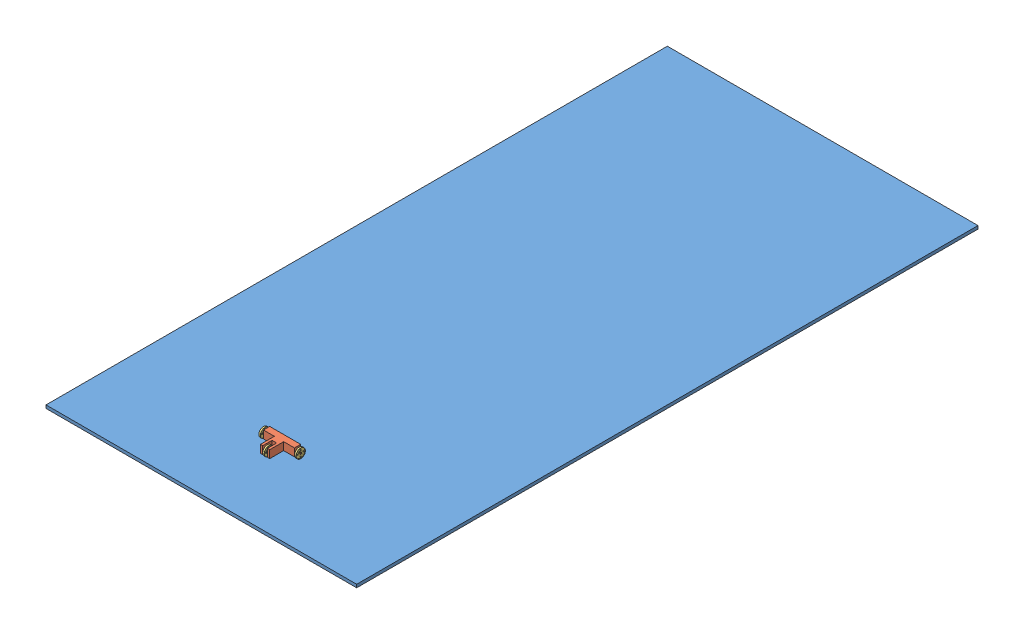
SolidWorks assembly Assy_RobotCruiseCtrl, configuration Default. Lengths in mm.
Overall size (1000 40 2000).
6 component instances, 3 part files, 3 mates.
Components (placement in the parent):
- Venue-1: Venue [Default] at origin size (1000 10 2000)
- Assy_WheelRobot-1: Assy_WheelRobot [Default] at (0 10 750) size (120 30 75)
  - Platform-1: Platform [Default] at origin size (120 25 65)
  - Wheel-1: Wheel [Default] at (-57.5 10 -10) x (0 -1 0) z (0 0 1) size (30 5 30)
  - Wheel-2: Wheel [Default] at (57.5 10 -10) x (0 -1 0) z (0 0 -1) size (30 5 30)
  - Wheel-4: Wheel [Default] at (0 10 35) x (0 -1 0) z (0 0 -1) size (30 5 30)
Mates (geometry in assembly coordinates):
- Distance1: distance = 750 mm aligned: plane of assembly through (0 0 0) normal (0 0 1); plane of Assy_WheelRobot-1/Platform-1 through (0 10 750) normal (0 0 1)
- Coincident2: coincident aligned: plane of Assy_WheelRobot-1/Platform-1 through (0 10 750) normal (1 0 0); plane of assembly through (0 0 0) normal (1 0 0)
- Tangent1: tangent anti-aligned: plane of Venue-1 through (0 5 0) normal (0 1 0); cylinder of Assy_WheelRobot-1/Wheel-2 through (55 20 740) axis (1 0 0) radius 15
